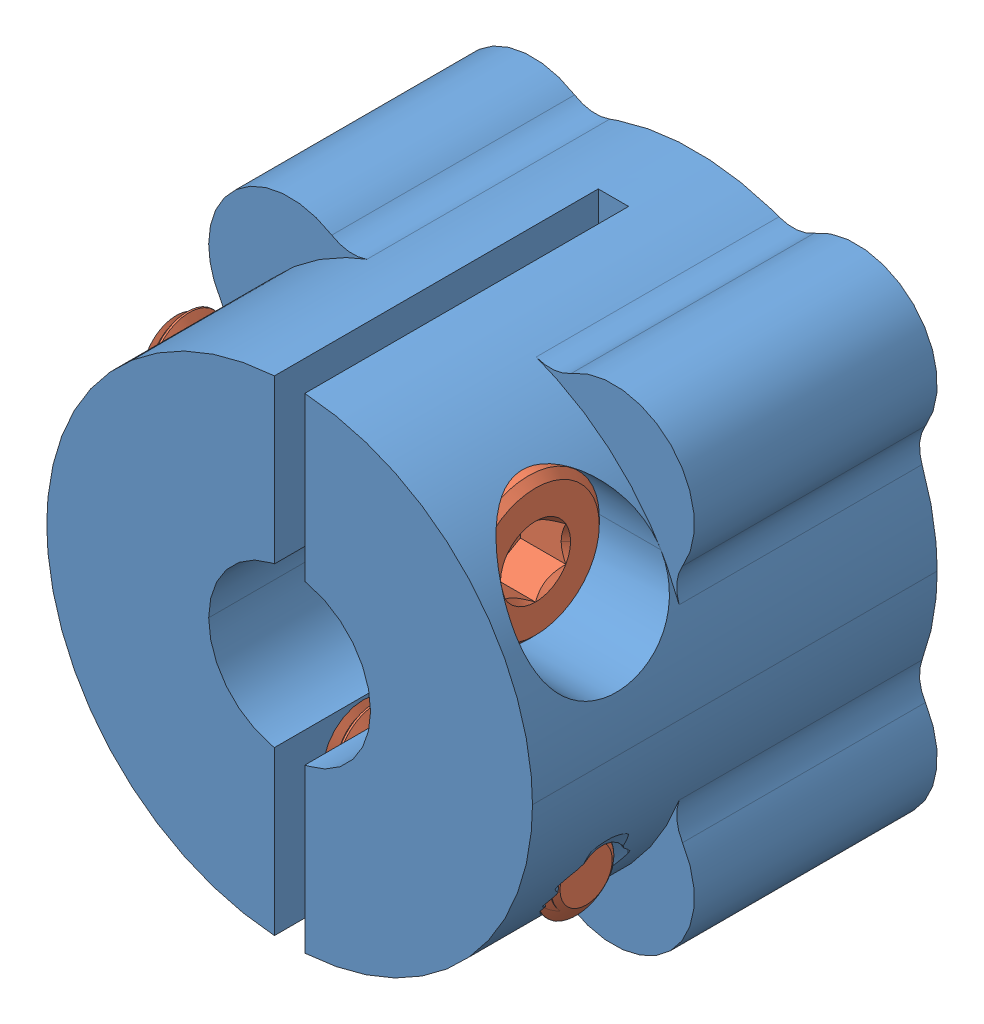
SolidWorks assembly 8mm Hyper Hub 1310-0016-0008, configuration Default. Lengths in mm.
Overall size (24 24 22).
3 component instances, 2 part files, 0 mates.
Components (placement in the parent):
- 1310-0016-0008.STEP-1: 1310-0016-0008.STEP [Default] at (-14.0123 7.4584 -7.173) size (24 24 22)
- 2800-0004-0014_90128A207.STEP-1: 2800-0004-0014_90128A207.STEP [Default] at (-3.7623 1.38 8.427) x (0 0 -1) z (1 0 0) size (7 7 18.01)
- 2800-0004-0014_90128A207.STEP-2: 2800-0004-0014_90128A207.STEP [Default] at (-24.2623 13.5369 8.427) x (0 0 1) z (-1 0 0) size (7 7 18.01)
